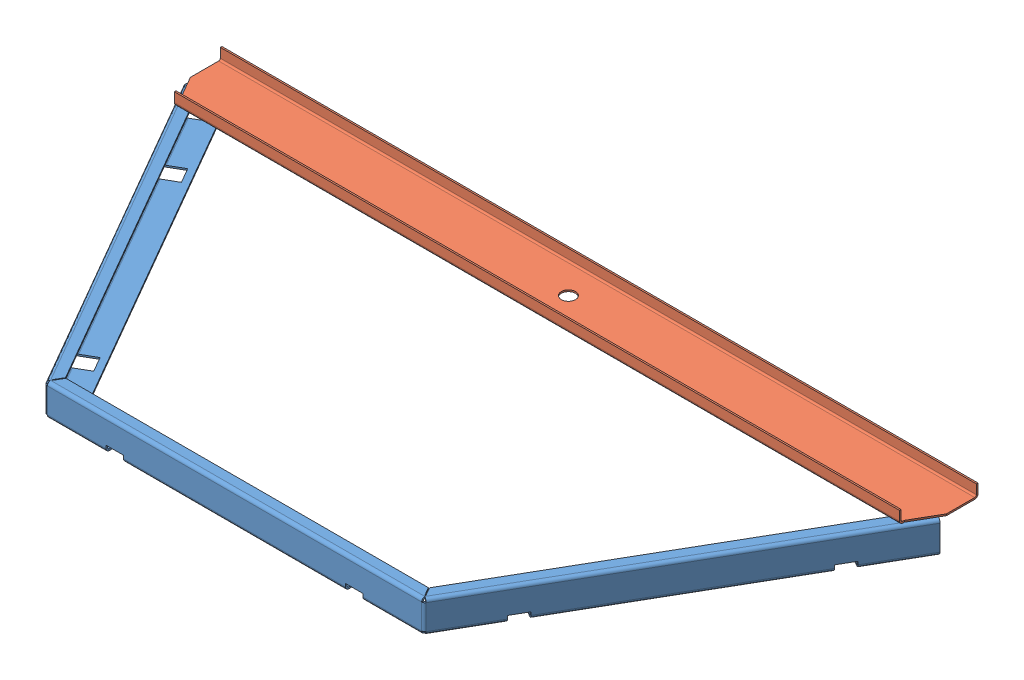
SolidWorks assembly GE-16009_ASM, configuration Default. Lengths in mm.
Overall size (1524 88.9 736.6).
2 component instances, 2 part files, 0 mates.
Components (placement in the parent):
- GE-16009-01-1: GE-16009-01 [Default] at origin size (1524 63.5 685.31)
- GE-16009-02-1: GE-16009-02 [Default] at (0 63.5 -669.8488) x (0 0 1) z (-1 0 0) size (127 25.4 1524)
